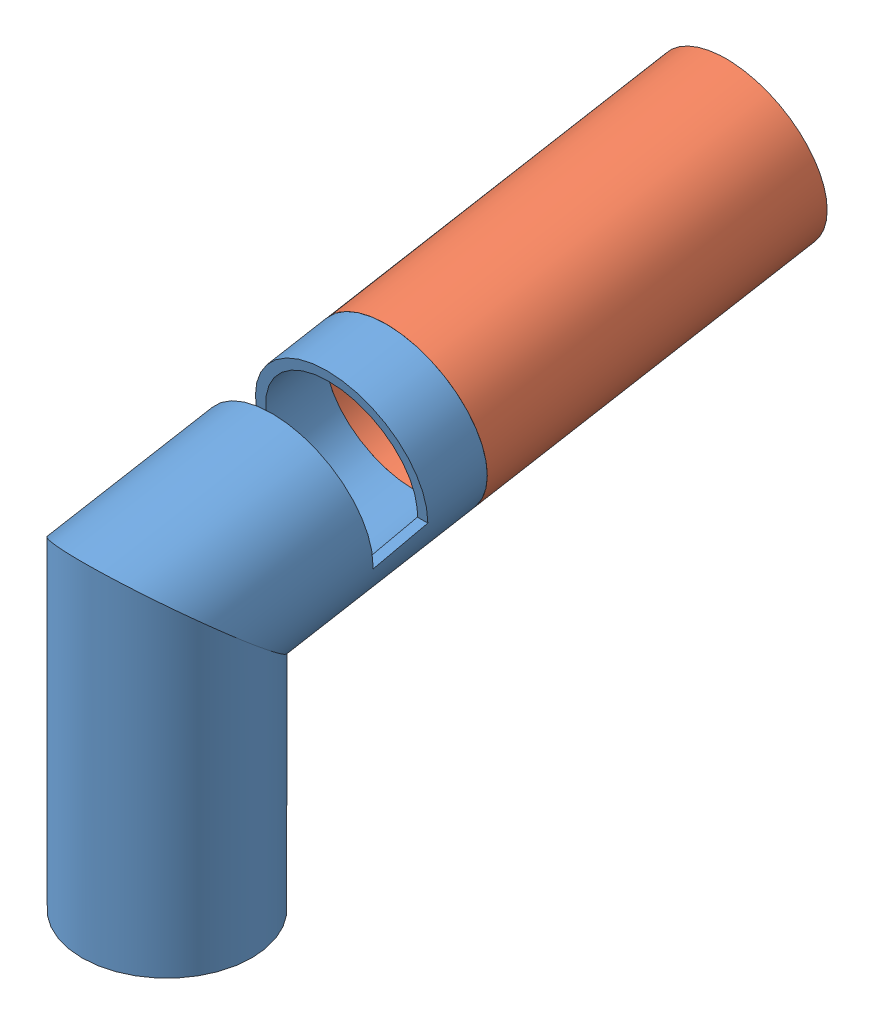
SolidWorks assembly cone assembly, configuration Default. Lengths in mm.
Overall size (50 134.42 198.33).
2 component instances, 2 part files, 1 mates.
Components (placement in the parent):
- angle cone3-1: angle cone3 [Default] at (58.7302 16.9755 168.1031) x (-1 0 0) z (0 -1 0) size (50 98.28 116.78)
- ball holder ver 2-2: ball holder ver 2 [Default] at (58.7302 109.1309 99.1666) x (1 0 0) z (0 0.984808 0.173648) size (50 101.6 50)
Mates (geometry in assembly coordinates):
- Coincident2: coincident anti-aligned: circle of angle cone3-1; circle of ball holder ver 2-2
